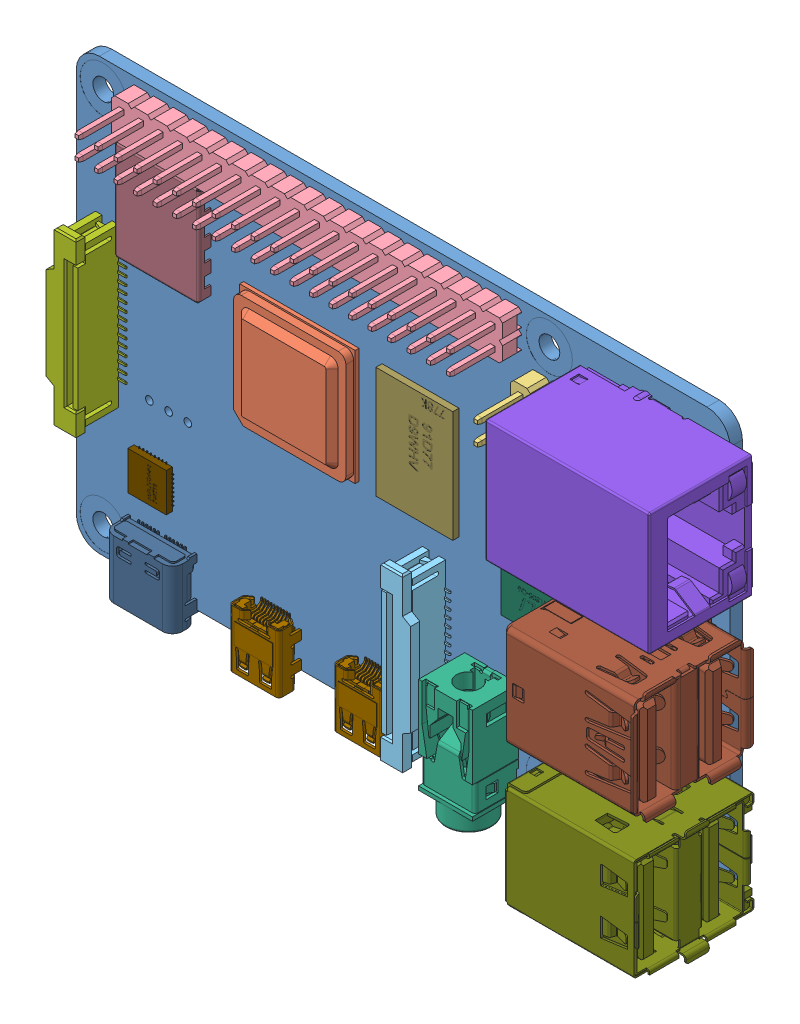
SolidWorks assembly Raspberry Pi 4 single-board controller, configuration Predeterminado. Lengths in mm.
Overall size (88.99 58.4 19.9).
20 component instances, 18 part files, 0 mates.
Components (placement in the parent):
- Raspberry Pi 4 single-board controller.step-1: Raspberry Pi 4 single-board controller.step [Predeterminado] at origin size (88.99 58.4 19.9)
  - PCB, RPi4ModelB.step-1: PCB, RPi4ModelB.step [Predeterminado] at (0 -28.8 -27.2) x (1 0 0) z (0 -1 0) size (85 1.6 56)
  - Broadcom BCM2711B0 CPU, RPi4ModelB.step-1: Broadcom BCM2711B0 CPU, RPi4ModelB.step [Predeterminado] at (-13.25 -24.3 -26.4) x (1 0 0) z (0 -1 0) size (15 2.3 15)
  - 2.54 mm DUPONT MALE PIN HEADER, POE, 2X2, RPi4ModelB.step-1: 2.54 mm DUPONT MALE PIN HEADER, POE, 2X2, RPi4ModelB.step [Predeterminado] at (19 -10.44 -26.4) x (1 0 0) z (0 -1 0) size (5.08 11.3 5.08)
  - 2.54 mm DUPONT MALE PIN HEADER, IO, 2X20, RPi4ModelB.step-1: 2.54 mm DUPONT MALE PIN HEADER, IO, 2X20, RPi4ModelB.step [Predeterminado] at (-10 -4.3 -26.4) x (1 0 0) z (0 -1 0) size (50.8 11.3 5.08)
  - Camera Connector, RPi4ModelB.step-1: Camera Connector, RPi4ModelB.step [Predeterminado] at (4 -45.3 -26.4) x (0 1 0) z (1 0 0) size (22.4 5.68 5.07)
  - Microphone Plug, RPi4ModelB.step-1: Microphone Plug, RPi4ModelB.step [Predeterminado] at (11.5 -50.45 -26.4) x (1 0 0) z (0 -1 0) size (7.23 7.55 15)
  - Display Connector, RPi4ModelB.step-1: Display Connector, RPi4ModelB.step [Predeterminado] at (-38.5 -28.8 -26.4) x (0 -1 0) z (-1 0 0) size (22.4 5.68 5.07)
  - Gigabit Ethernet Port, RPi4ModelB.step-1: Gigabit Ethernet Port, RPi4ModelB.step [Predeterminado] at (45.5 -11.05 -19.65) x (0 1 0) z (1 0 0) size (16.2 17.2 21.6)
  - Female Micro HDMI Connector, RPi4ModelB.step-1: Female Micro HDMI Connector, RPi4ModelB.step [Predeterminado] at (-3 -56.1875 -26.4) x (1 0 0) z (0 -1 0) size (6.5 3.51 7.5)
  - Female Micro HDMI Connector, RPi4ModelB.step-2: Female Micro HDMI Connector, RPi4ModelB.step [Predeterminado] at (-16.5 -56.1875 -26.4) x (1 0 0) z (0 -1 0) size (6.5 3.51 7.5)
  - Female USB Type C Connector, RPi4ModelB.step-1: Female USB Type C Connector, RPi4ModelB.step [Predeterminado] at (-31.3 -55.3419 -26.4) x (1 0 0) z (0 -1 0) size (8.94 3.96 7.9)
  - 2X USB3.0 PORTS, RPi4ModelB.step-1: 2X USB3.0 PORTS, RPi4ModelB.step [Predeterminado] at (37.07 -29.8 -26.4) x (1 0 0) z (0 -1 0) size (17.46 19.4 15.67)
  - 91D77 D9WHV 778K, 4 GB LPDDR4 SDRAM, RPi4ModelB.step-1: 91D77 D9WHV 778K, 4 GB LPDDR4 SDRAM, RPi4ModelB.step [Predeterminado] at (2.25 -24.3 -26.4) x (1 0 0) z (0 -1 0) size (10 0.8 14.5)
  - Cypress CYW43455 Wireless Module Cover, RPi4ModelB.step-1: Cypress CYW43455 Wireless Module Cover, RPi4ModelB.step [Predeterminado] at (-30.5 -14.3 -26.4) x (1 0 0) z (0 -1 0) size (11 1.6 13)
  - SD Card Slot, RPi4ModelB.step-1: SD Card Slot, RPi4ModelB.step [Predeterminado] at (-35.3 -28.8 -28) x (0 1 0) z (-1 0 0) size (11.95 1.45 11.4)
  - VIA VL805 PCIe USB 3.0 controller, RPi4ModelB.step-1: VIA VL805 PCIe USB 3.0 controller, RPi4ModelB.step [Predeterminado] at (17.5 -32.8 -26.4) x (1 0 0) z (0 -1 0) size (8.8 0.8 8.8)
  - 2X USB2.0 PORTS, RPi4ModelB.step-1: 2X USB2.0 PORTS, RPi4ModelB.step [Predeterminado] at (37.065 -47.8 -26.55) x (1 0 0) z (0 -1 0) size (17.86 19.16 15.33)
  - Broadcom BCM54213PE Gigabit Ethernet Transceiver, RPi4ModelB.step-1: Broadcom BCM54213PE Gigabit Ethernet Transceiver, RPi4ModelB.step [Predeterminado] at (16.5 -18.8 -26.4) x (1 0 0) z (0 -1 0) size (6.8 1 6.8)
  - MxL7704 Universal PMIC, RPi4ModelB.step-1: MxL7704 Universal PMIC, RPi4ModelB.step [Predeterminado] at (-32.5 -44.8 -26.4) x (1 0 0) z (0 -1 0) size (5.4 0.8 5.4)
